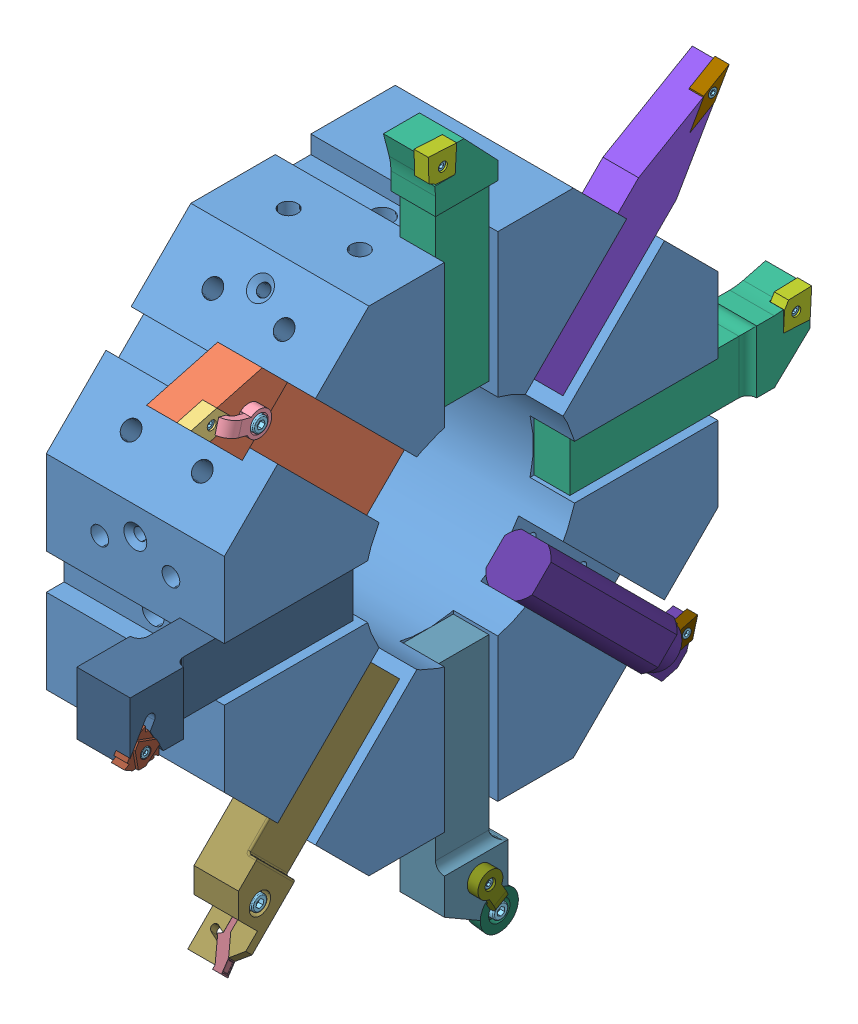
SolidWorks assembly 装配体1, configuration 默认. Lengths in mm.
Overall size (107 400.18 389.18).
37 component instances, 18 part files, 16 mates.
Components (placement in the parent):
- 转盘-1: 转盘 [默认] at (-40.074 7.4445 277.1639) size (100 277.16 277.16)
- 60度偏刀-1: 60度偏刀 [默认] at (34.926 103.1658 369.0963) x (0 0.707107 0.707107) z (1 0 0) size (144.45 42.34 32)
  - 60偏刀刀柄-1: 60偏刀刀柄 [默认] at (-21.8126 2.6791 0) size (140.7 35.85 25)
  - 60度偏刀刀片-2: 60度偏刀刀片 [默认] at (57.6325 17.0289 17) x (0.866025 0.5 0) z (0 0 1) size (25.98 15 8)
  - 60度偏刀挡片-1: 60度偏刀挡片 [默认] at (42.3835 13.9882 31) x (0.866025 0.5 0) z (0.5 -0.866025 0) size (25.45 12 14)
  - hexagon socket head cap screws gb-3: hexagon socket head cap screws gb [GB_FASTENER_SCREWS_HSHCS M3X5-N] at (58.5069 17.5337 24) x (0 0 -1) z (1 0 0) size (8 5.5 5.5)
  - hexagon socket head cap screws gb-4: hexagon socket head cap screws gb [GB_FASTENER_SCREWS_HSHCS M5X8-N] at (39.1874 7.5241 32) x (0 0 -1) z (0 -1 0) size (13 8.5 8.5)
- 90度偏刀-1: 90度偏刀 [默认] at (54.926 140.0957 295.9427) x (0 1 0) z (-1 0 0) size (130.88 39.9 25)
  - 90度偏刀刀柄-1: 90度偏刀刀柄 [默认] at (-29.3025 18.7788 0) size (130 39.26 25)
  - 90度偏刀刀-4: 90度偏刀刀 [默认] at (72.5922 0.3262 3) x (-0.998463 -0.055431 0) z (0 0 -1) size (15 16 8)
  - hexagon socket head cap screws gb-1: hexagon socket head cap screws gb [GB_FASTENER_SCREWS_HSHCS M3X5-N] at (52.9494 2.9461 -4) x (0 0 1) z (-1 0 0) size (8 5.5 5.5)
- 尖刀-1: 尖刀 [默认] at (44.926 96.205 198.6229) x (0 0.707107 -0.707107) z (-1 0 0) size (146.98 30 20)
  - 尖刀刀柄-1: 尖刀刀柄 [默认] at (-10.7101 7.2263 -10) size (145.98 30 20)
  - 尖刀刀片-2: 尖刀刀片 [默认] at (77.7707 7.2263 -10) size (32 8.57 8)
  - hexagon socket head cap screws gb-1: hexagon socket head cap screws gb [GB_FASTENER_SCREWS_HSHCS M3X5-N] at (80.7707 7.2263 -10) x (0 0 1) z (-1 0 0) size (8 5.5 5.5)
- 螺纹刀-1: 螺纹刀 [默认] at (44.926 10.1754 400.0756) x (0 0 1) z (1 0 0) size (136.42 44.29 31)
  - 螺纹刀刀柄-1: 螺纹刀刀柄 [默认] at (-16.4578 2.7309 -10) size (130 35 30)
  - 螺纹刀刀片-4: 螺纹刀刀片 [默认] at (72.0821 -15.7156 7) x (0.5 -0.866025 0) z (0 0 1) size (19.33 17.99 9)
  - hexagon socket head cap screws gb-1: hexagon socket head cap screws gb [GB_FASTENER_SCREWS_HSHCS M3X5-N] at (60.8427 17.7759 16) x (0 0 -1) z (1 0 0) size (8 5.5 5.5)
- 切断刀-2: 切断刀 [默认] at (47.426 -80.8733 348.4732) x (0 0.707107 -0.707107) z (1 0 0) size (139.16 30 29.87)
  - 切断刀刀柄-1: 切断刀刀柄 [默认] at (18.1542 12.0268 -12.5) size (135 30 25)
  - 切断刀刀片-3: 切断刀刀片 [默认] at (-84.6401 2.0268 7.8462) x (0.866025 0 0.5) z (0 -1 0) size (21.49 20.95 5)
  - hexagon socket head cap screws gb-1: hexagon socket head cap screws gb [GB_FASTENER_SCREWS_HSHCS M5X8-N] at (-56.8458 10.0268 12.5) x (0 0 -1) z (0.056624 -0.998396 0) size (13 8.5 8.5)
- 球头车刀-1: 球头车刀 [默认] at (47.426 -180.2868 290.9491) x (0 -1 0) z (1 0 0) size (146.02 44.83 31)
  - 球头车刀刀柄-1: 球头车刀刀柄 [默认] at (-77.8026 13.7853 -12.5) size (137.77 35.85 25)
  - 球头车刀刀片-1: 球头车刀刀片 [默认] at (4.2323 29.6303 12.5) x (-0.923728 -0.383049 0) z (0 0 -1) size (21.4 21.4 8)
  - 球头车刀挡片-1: 球头车刀挡片 [默认] at (-13.6064 25.0944 18.5) x (0.866025 0.5 0) z (0.5 -0.866025 0) size (25.45 12 14)
  - hexagon socket head cap screws gb-1: hexagon socket head cap screws gb [GB_FASTENER_SCREWS_HSHCS M3X5-N] at (-16.8026 18.6303 17.5) x (0 0 -1) z (1 0 0) size (8 5.5 5.5)
  - hexagon socket head cap screws gb-2: hexagon socket head cap screws gb [GB_FASTENER_SCREWS_HSHCS M5X8-N] at (4.2323 29.6303 13.5) x (0 0 -1) z (1 0 0) size (13 8.5 8.5)
- 镗刀-1: 镗刀 [默认] at (45.0538 -77.6481 190.3057) x (0 0.707107 -0.707107) z (0 -0.707107 -0.707107) size (31.47 25.98 130)
  - 镗刀刀柄-1: 镗刀刀柄 [默认] at (-3.2581 2.8626 -65) size (29.74 25.98 130)
  - 镗刀刀片-2: 镗刀刀片 [默认] at (5.6946 -2.1374 57.4707) x (1 0 0) z (0 1 0) size (19.05 11 6)
  - hexagon socket head cap screws gb-1: hexagon socket head cap screws gb [GB_FASTENER_SCREWS_HSHCS M3X5-N] at (6.6683 3.8626 57.4707) x (0 -1 0) z (0 0 1) size (8 5.5 5.5)
- 90度偏刀-3: 90度偏刀 [默认] at (54.926 26.2233 147.439) x (0 0 -1) z (-1 0 0) size (130.88 39.9 25)
  - 90度偏刀刀柄-1: 90度偏刀刀柄 [默认] at (-29.3025 18.7788 0) size (130 39.26 25)
  - 90度偏刀刀-4: 90度偏刀刀 [默认] at (72.5922 0.3262 3) x (-0.998463 -0.055431 0) z (0 0 -1) size (15 16 8)
  - hexagon socket head cap screws gb-1: hexagon socket head cap screws gb [GB_FASTENER_SCREWS_HSHCS M3X5-N] at (52.9494 2.9461 -4) x (0 0 1) z (-1 0 0) size (8 5.5 5.5)
Mates (geometry in assembly coordinates):
- 重合1: coincident anti-aligned: plane of 转盘-1 through (34.926 -120.5318 127.9743) normal (1 0 0); plane of 60度偏刀-1/60偏刀刀柄-1 through (34.926 85.8475 355.5669) normal (-1 0 0)
- 重合2: coincident anti-aligned: plane of 转盘-1 through (59.926 -141.745 149.1875) normal (0 0.707107 -0.707107); plane of 60度偏刀-1/60偏刀刀柄-1 through (54.926 39.8856 330.8181) normal (0 -0.707107 0.707107)
- 重合3: coincident anti-aligned: plane of 转盘-1 through (34.926 -131.1384 262.1639) normal (1 0 0); plane of 90度偏刀-1/90度偏刀刀柄-1 through (34.926 110.7933 277.1639) normal (-1 0 0)
- 重合4: coincident anti-aligned: plane of 转盘-1 through (59.926 -131.1384 292.1639) normal (0 0 -1); plane of 90度偏刀-1/90度偏刀刀柄-1 through (34.926 70.7933 292.1639) normal (0 0 1)
- 重合5: coincident anti-aligned: plane of 转盘-1 through (34.926 -141.745 405.1402) normal (1 0 0); plane of 尖刀-1/尖刀刀柄-1 through (34.926 83.5221 201.0863) normal (-1 0 0)
- 重合6: coincident anti-aligned: plane of 转盘-1 through (59.926 -141.745 405.1402) normal (0 0.707107 0.707107); plane of 尖刀-1/尖刀刀柄-1 through (34.926 42.8634 220.5317) normal (0 -0.707107 -0.707107)
- 重合8: coincident anti-aligned: plane of 转盘-1 through (34.926 22.4445 138.5809) normal (1 0 0); plane of 螺纹刀-1/螺纹刀刀柄-1 through (34.926 7.4445 383.6178) normal (-1 0 0)
- 重合9: coincident anti-aligned: plane of 转盘-1 through (59.926 22.4445 138.5809) normal (0 -1 0); plane of 螺纹刀-1/螺纹刀刀柄-1 through (54.926 22.4445 338.6178) normal (0 1 0)
- 重合12: coincident anti-aligned: plane of 转盘-1 through (34.926 156.634 149.1875) normal (1 0 0); plane of 切断刀-2/切断刀刀柄-1 through (34.926 -59.5321 344.1405) normal (-1 0 0)
- 重合13: coincident anti-aligned: plane of 转盘-1 through (59.926 135.4208 127.9743) normal (0 0.707107 0.707107); plane of 切断刀-2/切断刀刀柄-1 through (54.926 -112.5651 375.9603) normal (0 -0.707107 -0.707107)
- 重合14: coincident anti-aligned: plane of 转盘-1 through (34.926 146.0274 292.1639) normal (1 0 0); plane of 球头车刀-1/球头车刀刀柄-1 through (34.926 -102.4842 277.1639) normal (-1 0 0)
- 重合15: coincident anti-aligned: plane of 转盘-1 through (59.926 146.0274 262.1639) normal (0 0 1); plane of 球头车刀-1/球头车刀刀柄-1 through (54.926 -52.4842 262.1639) normal (0 0 -1)
- 重合16: coincident anti-aligned: plane of 转盘-1 through (34.926 135.4208 426.3534) normal (1 0 0); plane of 镗刀-1/镗刀刀柄-1 through (34.926 -99.3973 162.5575) normal (-1 0 0)
- 重合17: coincident anti-aligned: plane of 转盘-1 through (59.926 135.4208 426.3534) normal (0 0.707107 -0.707107); plane of 镗刀-1/镗刀刀柄-1 through (55.4164 -113.8862 177.0464) normal (0 -0.707107 0.707107)
- 重合20: coincident anti-aligned: plane of 转盘-1 through (34.926 -7.5555 415.7468) normal (1 0 0); plane of 90度偏刀-3/90度偏刀刀柄-1 through (34.926 7.4445 176.7414) normal (-1 0 0)
- 重合21: coincident anti-aligned: plane of 转盘-1 through (59.926 -7.5555 415.7468) normal (0 1 0); plane of 90度偏刀-3/90度偏刀刀柄-1 through (34.926 -7.5555 216.7414) normal (0 -1 0)
